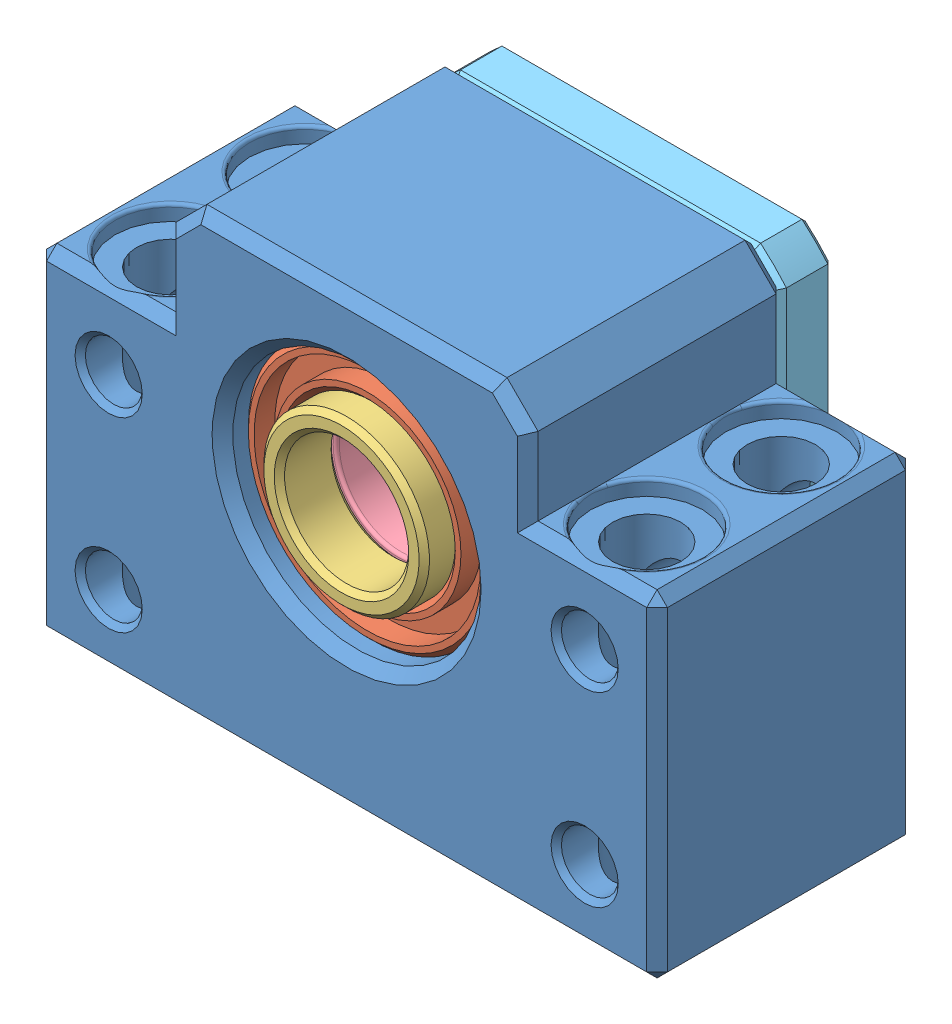
SolidWorks assembly BK12, configuration Default. Lengths in mm.
Overall size (60 43 35.16).
15 component instances, 8 part files, 30 mates.
Components (placement in the parent):
- BK12-1-1: BK12-1 [Default] at (-11.028 26.197 -11.9785) size (60 43 25)
- BK12-2-5: BK12-2 [Default] at (-11.028 8.197 8.0215) size (24 24 3)
- BK12-3-4: BK12-3 [Default] at (-11.028 8.197 8.0215) size (16 16 5.5)
- 6001-Bearing-3: 6001-Bearing [Default] at (-11.028 8.197 0.0215) size (28 28 8)
- 6001-Bearing-4: 6001-Bearing [Default] at (-11.028 8.197 -7.9785) size (28 28 8)
- BK12-2-6: BK12-2 [Default] at (-11.028 8.197 -7.9785) x (-1 0 0) z (0 0 -1) size (24 24 3)
- BK12-3-5: BK12-3 [Default] at (-11.028 8.197 -13.4785) size (16 16 5.5)
- BK12-4-1: BK12-4 [Default] at (-11.028 8.197 -16.9785) size (34 34 9)
- socket head cap screw_din-2: socket head cap screw_din [DIN 912 M3 x 8 --- 8N] at (-22.878 20.047 -16.9785) x (0 0 1) z (-1 0 0) size (11 5.5 5.5)
- socket head cap screw_din-3: socket head cap screw_din [DIN 912 M3 x 8 --- 8N] at (-22.878 -3.653 -16.9785) x (0 0 1) z (-1 0 0) size (11 5.5 5.5)
- socket head cap screw_din-4: socket head cap screw_din [DIN 912 M3 x 8 --- 8N] at (0.822 20.047 -16.9785) x (0 0 1) z (-1 0 0) size (11 5.5 5.5)
- socket head cap screw_din-5: socket head cap screw_din [DIN 912 M3 x 8 --- 8N] at (0.822 -3.653 -16.9785) x (0 0 1) z (-1 0 0) size (11 5.5 5.5)
- BK12-5-1: BK12-5 [Default] at (-11.028 8.197 -21.4785) size (19 19 8.53)
- socket set screw cup point_din-18: socket set screw cup point_din [DIN 916 - M3 x 4-N] at (-3.3011 15.9239 -18.7785) x (-0.707107 -0.707107 0) z (-0.70706 0.70706 -0.011443) size (4 3 3)
- socket set screw cup point_din-19: socket set screw cup point_din [DIN 916 - M3 x 4-N] at (-18.7549 15.9239 -18.7785) x (0.707107 -0.707107 0) z (0 0 1) size (4 3 3)
Mates (geometry in assembly coordinates):
- Concentric12: concentric aligned: cylinder of 2-5 through (-11.028 8.197 11.0215) axis (0 0 -1) radius 8; cylinder of 3-4 through (-11.028 8.197 13.5215) axis (0 0 -1) radius 8
- Coincident10: coincident aligned: plane of 2-5 through (-11.028 8.197 8.0215) normal (0 0 -1); plane of 3-4 through (-11.028 8.197 8.0215) normal (0 0 -1)
- Concentric13: concentric aligned: cylinder of 1-1 through (-11.028 8.197 13.0215) axis (0 0 -1) radius 12; cylinder of 2-5 through (-11.028 8.197 11.0215) axis (0 0 -1) radius 12
- Coincident11: coincident aligned: plane of 1-1 through (-11.028 8.197 8.0215) normal (0 0 -1); plane of 2-5 through (-11.028 8.197 8.0215) normal (0 0 -1)
- Concentric14: concentric aligned: cylinder of 1-1 through (-11.028 8.197 8.0215) axis (0 0 -1) radius 14; cylinder of 6001-Bearing-3 through (-11.028 8.197 8.0215) axis (0 0 -1) radius 14
- Coincident12: coincident anti-aligned: plane of 1-1 through (-11.028 8.197 8.0215) normal (0 0 -1); plane of 6001-Bearing-3 through (-11.028 8.197 8.0215) normal (0 0 1)
- Concentric15: concentric aligned: cylinder of 1-1 through (-11.028 8.197 8.0215) axis (0 0 -1) radius 14; cylinder of 6001-Bearing-4 through (-11.028 8.197 0.0215) axis (0 0 -1) radius 14
- Coincident13: coincident anti-aligned: plane of 6001-Bearing-3 through (-11.028 8.197 0.0215) normal (0 0 -1); plane of 6001-Bearing-4 through (-11.028 8.197 0.0215) normal (0 0 1)
- Concentric16: concentric anti-aligned: cylinder of 2-6 through (-11.028 8.197 -10.9785) axis (0 0 1) radius 8; cylinder of 3-5 through (-11.028 8.197 -7.9785) axis (0 0 -1) radius 8
- Coincident14: coincident aligned: plane of 2-6 through (-11.028 8.197 -7.9785) normal (0 0 1); plane of 3-5 through (-11.028 8.197 -7.9785) normal (0 0 1)
- Concentric17: concentric anti-aligned: cylinder of 1-1 through (-11.028 8.197 8.0215) axis (0 0 -1) radius 14; cylinder of 2-6 through (-11.028 8.197 -10.9785) axis (0 0 1) radius 12
- Coincident15: coincident anti-aligned: plane of 6001-Bearing-4 through (-11.028 8.197 -7.9785) normal (0 0 -1); plane of 2-6 through (-11.028 8.197 -7.9785) normal (0 0 1)
- Concentric18: concentric anti-aligned: cylinder of 1-1 through (-11.028 8.197 8.0215) axis (0 0 -1) radius 14; cylinder of 4-1 through (-11.028 8.197 -11.9785) axis (0 0 1) radius 14
- Angle1: planar angle = 0 rad aligned: plane of 4-1 through (-25.528 25.197 -7.9785) normal (0 1 0); plane of 1-1 through (6.472 26.197 13.0215) normal (0 1 0)
- Coincident17: coincident anti-aligned: plane of 1-1 through (18.972 -16.803 -11.9785) normal (0 0 -1); plane of 4-1 through (-11.028 8.197 -11.9785) normal (0 0 1)
- Concentric19: concentric aligned: cylinder of 4-1 through (-22.878 20.047 -7.9785) axis (0 0 -1) radius 1.5; cylinder of socket head cap screw_din-2 through (-22.878 20.047 -48.7285) axis (0 0 -1) radius 1.5
- Coincident18: coincident anti-aligned: plane of 4-1 through (-22.878 20.047 -13.9785) normal (0 0 -1); plane of socket head cap screw_din-2 through (-22.878 22.797 -13.9785) normal (0 0 1)
- Concentric20: concentric aligned: cylinder of 4-1 through (-22.878 -3.653 -13.9785) axis (0 0 -1) radius 4; cylinder of socket head cap screw_din-3 through (-22.878 -3.653 -48.7285) axis (0 0 -1) radius 2.75
- Coincident19: coincident anti-aligned: plane of 4-1 through (-22.878 -3.653 -13.9785) normal (0 0 -1); plane of socket head cap screw_din-3 through (-22.878 -0.903 -13.9785) normal (0 0 1)
- Concentric21: concentric aligned: cylinder of 4-1 through (0.822 20.047 -7.9785) axis (0 0 -1) radius 1.5; cylinder of socket head cap screw_din-4 through (0.822 20.047 -48.7285) axis (0 0 -1) radius 2.75
- Coincident20: coincident anti-aligned: plane of 4-1 through (0.822 20.047 -13.9785) normal (0 0 -1); plane of socket head cap screw_din-4 through (0.822 22.797 -13.9785) normal (0 0 1)
- Concentric22: concentric aligned: cylinder of 4-1 through (0.822 -3.653 -13.9785) axis (0 0 -1) radius 4; cylinder of socket head cap screw_din-5 through (0.822 -3.653 -48.7285) axis (0 0 -1) radius 2.75
- Coincident21: coincident anti-aligned: plane of 4-1 through (0.822 -3.653 -13.9785) normal (0 0 -1); plane of socket head cap screw_din-5 through (0.822 -0.903 -13.9785) normal (0 0 1)
- Coincident22: coincident anti-aligned: plane of 3-5 through (-11.028 8.197 -13.4785) normal (0 0 -1); plane of 5-1 through (-11.028 8.197 -13.4785) normal (0 0 1)
- Concentric23: concentric anti-aligned: circle of 3-5; circle of 5-1
- Concentric35: concentric anti-aligned: cylinder of 5-1 through (-20.529 17.698 -18.7785) axis (0.707107 -0.707107 0) radius 1.5; cylinder of socket set screw cup point_din-19 through (-27.7351 24.9041 -18.7785) axis (-0.707107 0.707107 0) radius 1.5
- Tangent3: tangent aligned: cylinder of 5-1 through (-11.028 8.197 -13.4785) axis (0 0 -1) radius 10.9275; plane of socket set screw cup point_din-19 through (-18.7549 15.9239 -18.7785) normal (-0.707107 0.707107 0)
- Concentric36: concentric anti-aligned: cylinder of 5-1 through (-1.527 17.698 -18.7785) axis (-0.707107 -0.707107 0) radius 1.5; cylinder of socket set screw cup point_din-18 through (5.6792 24.9041 -18.7785) axis (0.707107 0.707107 0) radius 1.5
- Tangent4: tangent aligned: cylinder of 5-1 through (-11.028 8.197 -13.4785) axis (0 0 -1) radius 10.9275; plane of socket set screw cup point_din-18 through (-3.3011 15.9239 -18.7785) normal (0.707107 0.707107 0)
- Angle2: planar angle = 0 rad aligned: plane of 5-1 through (-16.428 17.697 -13.4785) normal (0 1 0); plane of 4-1 through (-25.528 25.197 -7.9785) normal (0 1 0)
